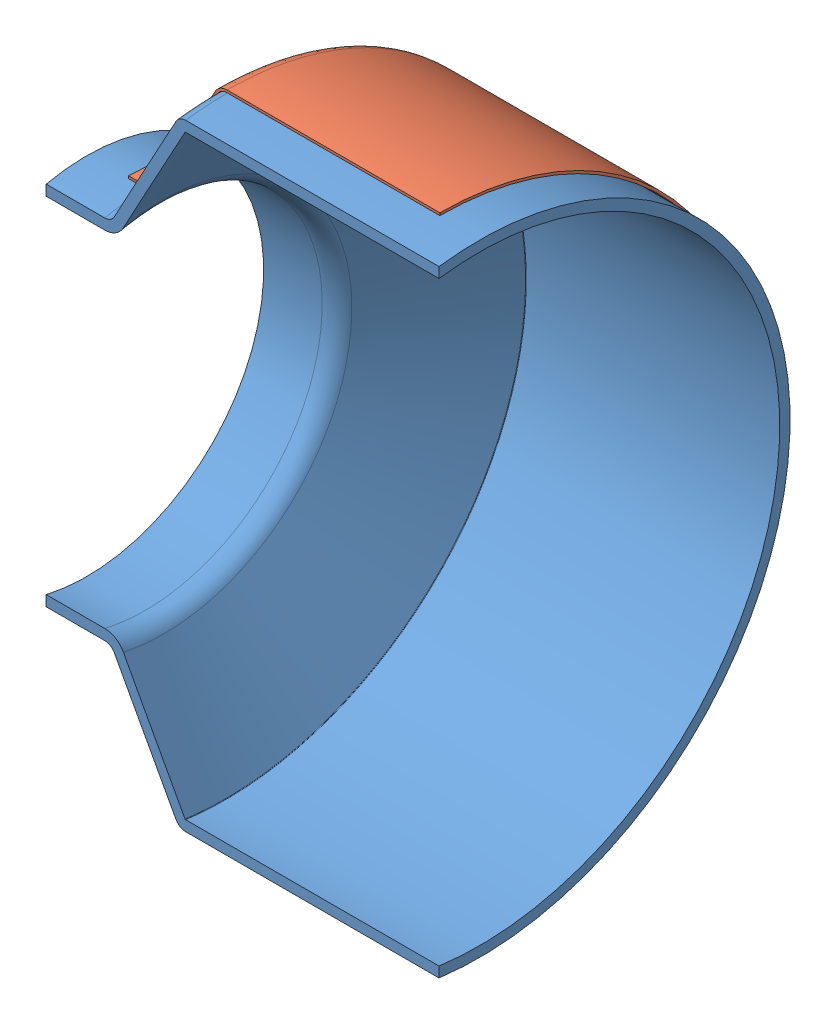
SolidWorks assembly FVTX Cage Lamination, configuration Finished cage on lamination tool. Lengths in mm.
Overall size (241.88 387.46 218.1).
2 component instances, 2 part files, 3 mates.
Components (placement in the parent):
- FVTX Cage Laminating Form-1: FVTX Cage Laminating Form [Default] at origin
- FVTX Cage Shell-1: FVTX Cage Shell [Pre-Machined] at (0.0684 0 0)
Mates (geometry in assembly coordinates):
- Concentric1: concentric aligned: cylinder of FVTX Cage Laminating Form-1 through (0 0 0) axis (1 0 0) radius 191.311; cylinder of FVTX Cage Shell-1 through (0.0684 0 0) axis (1 0 0) radius 191.7625
- Coincident1: coincident aligned: plane of FVTX Cage Laminating Form-1 through (0 0 0) normal (0 1 0); plane of FVTX Cage Shell-1 through (0.0684 0 0) normal (0 1 0)
- Distance1: distance = 25.4 mm aligned: plane of FVTX Cage Shell-1 through (-3.5782 -115.675 0) normal (-1 0 0); plane of FVTX Cage Laminating Form-1 through (-28.9782 0 0) normal (-1 0 0)
